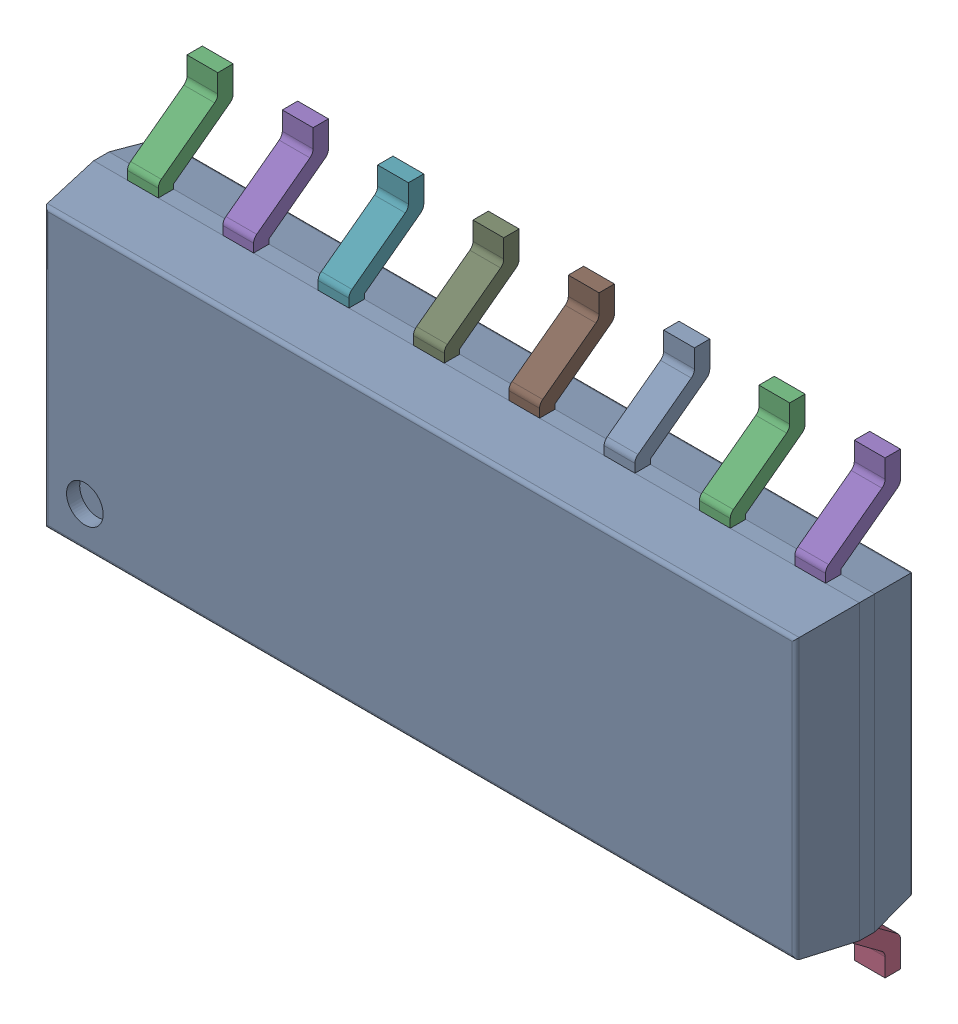
SolidWorks assembly IC17_1.step, configuration Default. Lengths in mm.
Overall size (10.2 6 1.75).
3 component instances, 2 part files, 0 mates.
Components (placement in the parent):
- 6348803008_1.step-3: 6348803008_1.step [Default] at (520.065 262.098 0) x (0 1 0) z (0 0 1) size (6 10.2 1.75)
  - Body-14_1.step-8: Body-14_1.step [Default] at origin size (3.9 10.2 1.57)
  - PinsArrayLR-15_1.step-8: PinsArrayLR-15_1.step [Default] at origin size (6 9.3 1)
